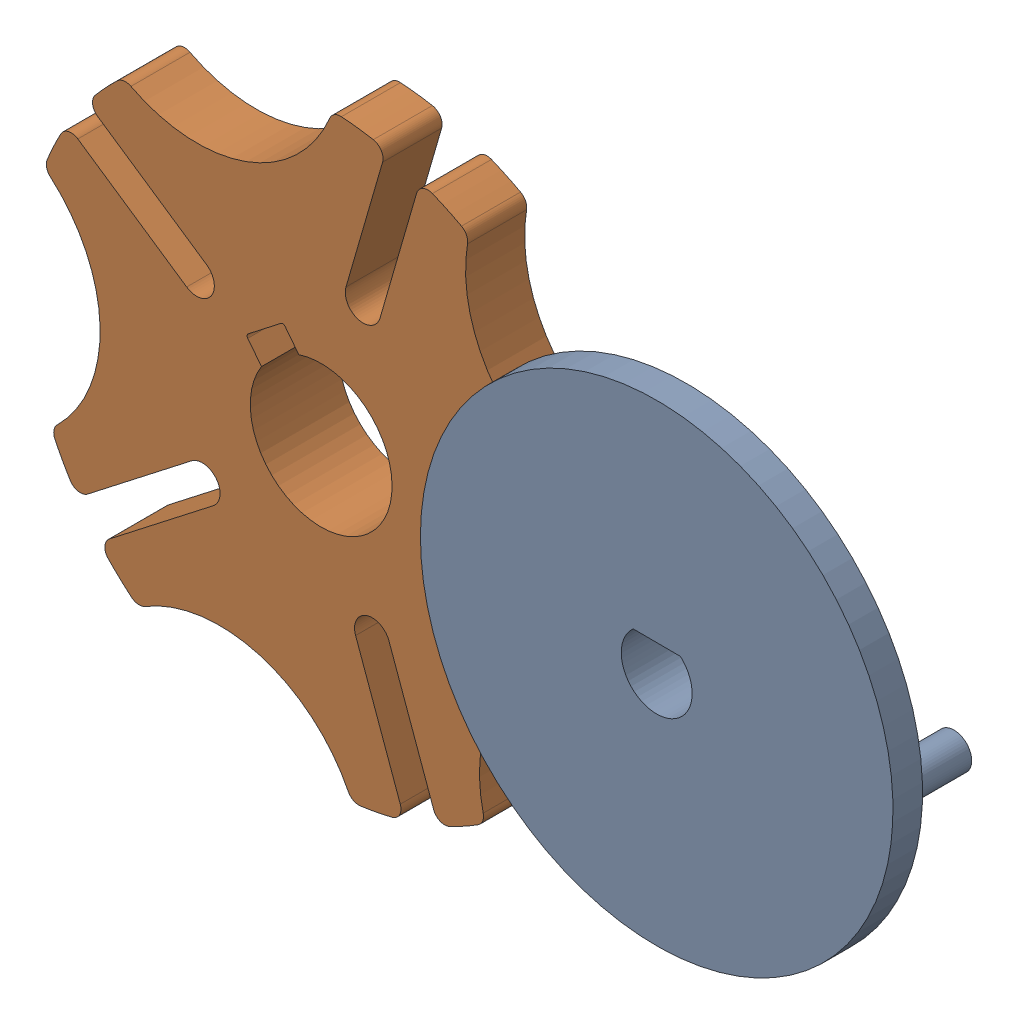
SolidWorks assembly GenevaWheelMechanism, configuration Default. Lengths in mm.
Overall size (85.9 68.64 10).
2 component instances, 2 part files, 6 mates.
Components (placement in the parent):
- GenevaDriveWheel-1: GenevaDriveWheel [Default] at (50.514 -1.048 7.5) x (-0.999987 0.005075 0) z (0 0 -1) size (40 40 7.5)
- GenevaWheel-1: GenevaWheel [Default] at (0 0 2.5) x (0.789564 0.613668 0) z (0 0 1) size (47.83 49.76 7.5)
Mates (geometry in assembly coordinates):
- Coincident1: coincident anti-aligned: plane of GenevaWheel-1 through (0 0 0) normal (0 0 -1)
- Concentric1: concentric: cylinder of GenevaWheel-1 through (0 0 0) axis (0 0 1) radius 15
- Coincident4: coincident anti-aligned: plane of GenevaPinWheel-1 through (30.9 0 7.5) normal (0 0 -1); plane of GenevaWheel-1 through (0 0 7.5) normal (0 0 1)
- Distance2: distance = 30.9 mm: line of GenevaPinWheel-1 through (30.9 0 10) axis (0 0 -1); line of GenevaWheel-1 through (0 0 0) axis (0 0 1)
- Coincident7: coincident: line of GenevaPinWheel-1 through (30.9 0 10) axis (0 0 -1)
- Tangent1: tangent anti-aligned: cylinder of GenevaPinWheel-1 through (19.511 -14.1494 3) axis (0 0 1) radius 1.5; plane of GenevaWheel-1
